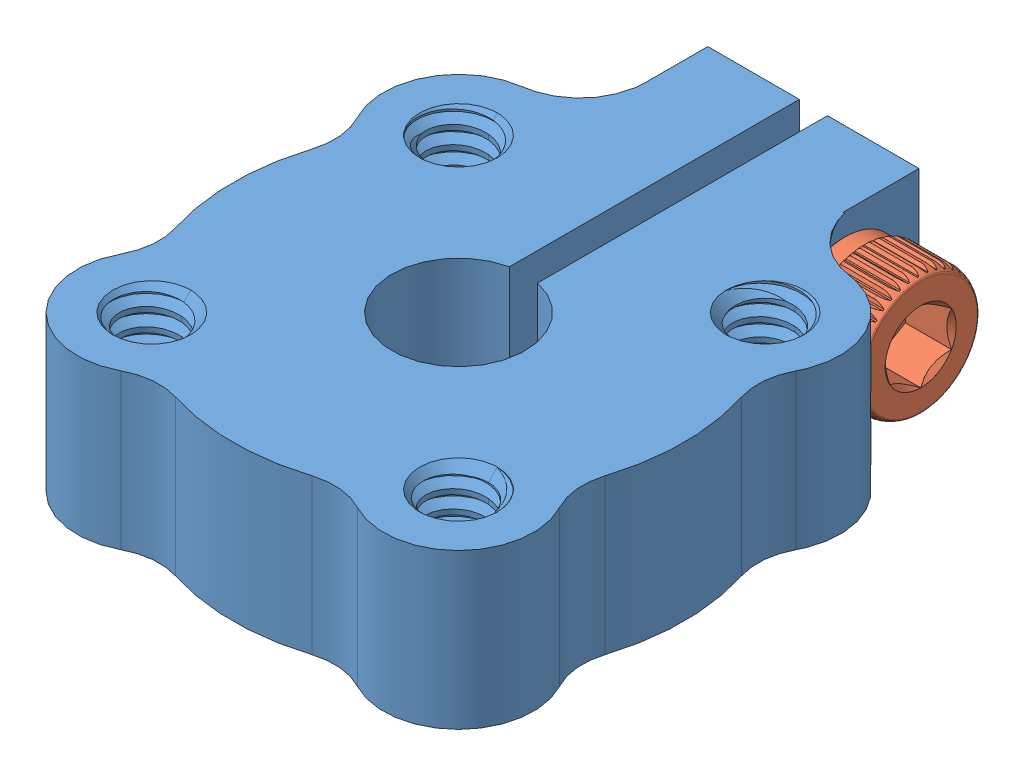
SolidWorks assembly 545616 assembly.STEP, configuration Default. Lengths in mm.
Overall size (20.57 9.53 26.29).
2 component instances, 2 part files, 0 mates.
Components (placement in the parent):
- 545616.STEP-1: 545616.STEP [Default] at (-21.6153 -9.061 17.0898) size (20.57 9.53 26.29)
- 632110_90128A121.STEP-1: 632110_90128A121.STEP [Default] at (-54.9528 -3.0285 4.5168) x (0 0 1) z (-1 0 0) size (5.61 5.61 13.03)
